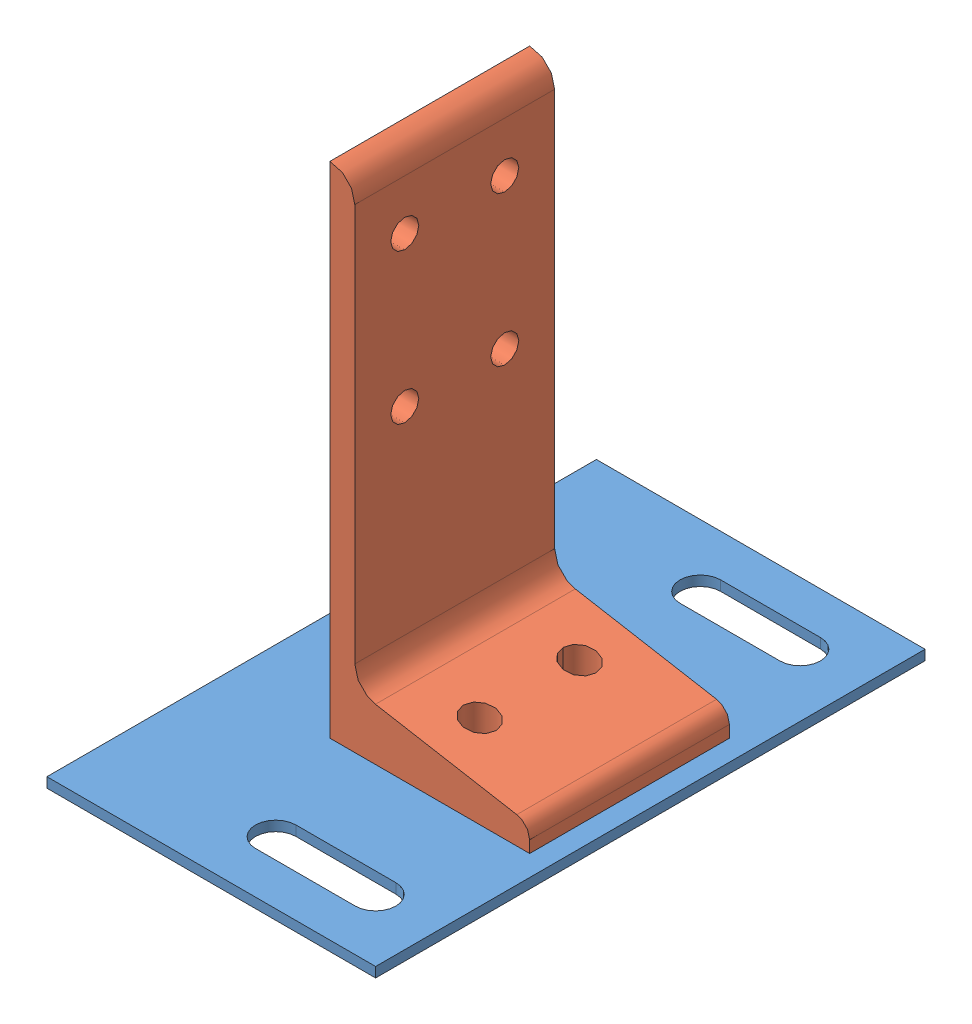
SolidWorks assembly 8020-2385-DEFAULT, configuration Default. Lengths in mm.
Overall size (83.57 129.54 139.7).
2 component instances, 2 part files, 0 mates.
Components (placement in the parent):
- 8020-2385-DEFAULT_238508-1: 8020-2385-DEFAULT_238508 [Default] at (-2.8656 4.3503 -15.9353) size (83.57 2.54 139.7)
- 8020-2385-DEFAULT_238509-2: 8020-2385-DEFAULT_238509 [Default] at (29.7024 -6.8087 -25.6289) size (50.8 127 50.8)
